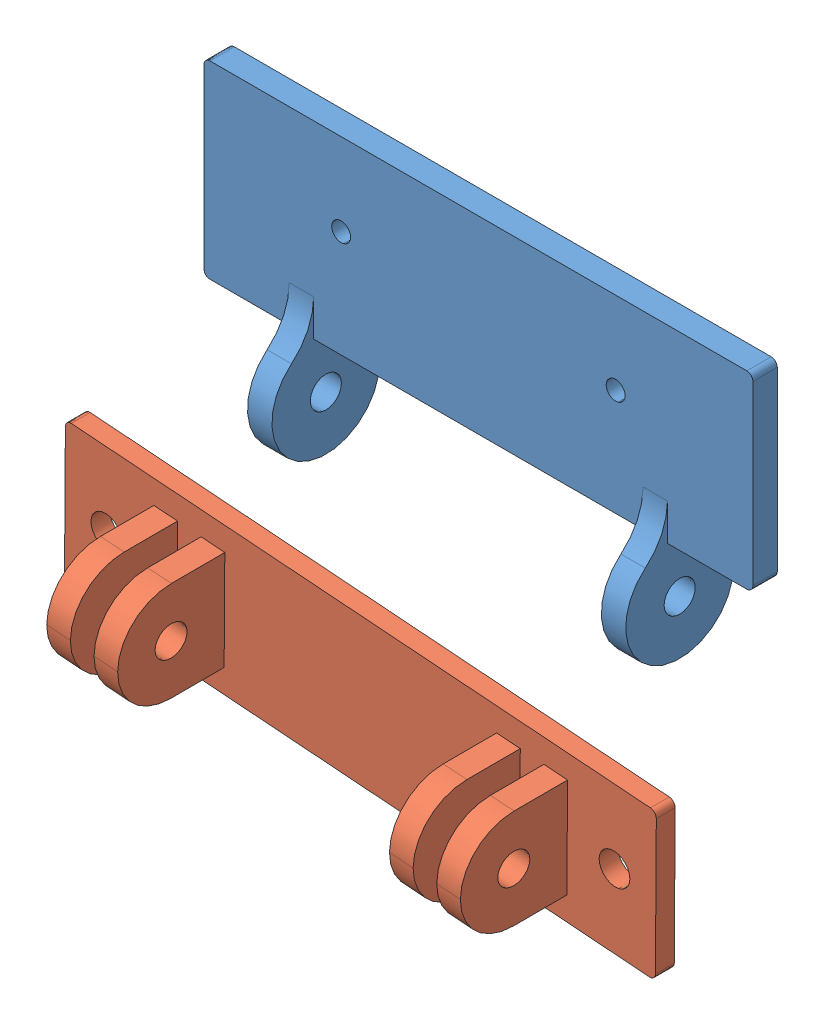
SolidWorks assembly Baugr2, configuration Standard. Lengths in mm.
Overall size (102.46 80.75 42.64).
2 component instances, 2 part files, 0 mates.
Components (placement in the parent):
- cameraHold-1: cameraHold [Standard] at (4.4771 15.3911 88) size (90 48.36 17.7)
- stand1-1: stand1 [Standard] at (-52.1099 -32.7476 100.281) x (0.998642 -0.042645 0.029927) z (-0.031382 -0.033853 0.998934) size (100 25 20)
